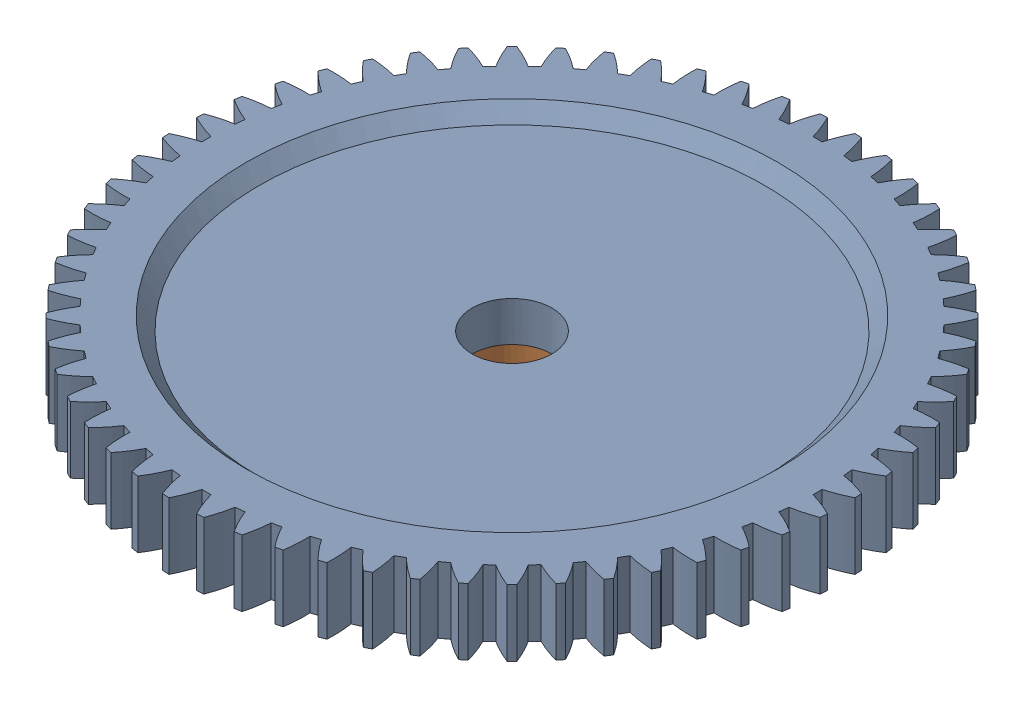
SolidWorks assembly White_Idler_Gear_Assembly, configuration Default. Lengths in mm.
Overall size (49.56 14 49.56).
2 component instances, 2 part files, 2 mates.
Components (placement in the parent):
- White_Idler_Gear-3: White_Idler_Gear [Default] at (51.194 12.4424 16.337) size (49.56 5 49.56)
- White_Idler_Gear_Small-3: White_Idler_Gear_Small [Default] at (51.194 3.4424 16.337) size (15.96 10 15.96)
Mates (geometry in assembly coordinates):
- Coincident1: coincident anti-aligned: plane of White Idler Gear-3 through (51.194 13.4424 16.337) normal (0 -1 0); plane of White Idler Gear Small-3 through (48.2537 13.4424 14.6641) normal (0 1 0)
- Concentric1: concentric anti-aligned: cylinder of White Idler Gear-3 through (51.194 17.4424 16.337) axis (0 -1 0) radius 3; cylinder of White Idler Gear Small-3 through (51.194 3.4424 16.337) axis (0 1 0) radius 3
